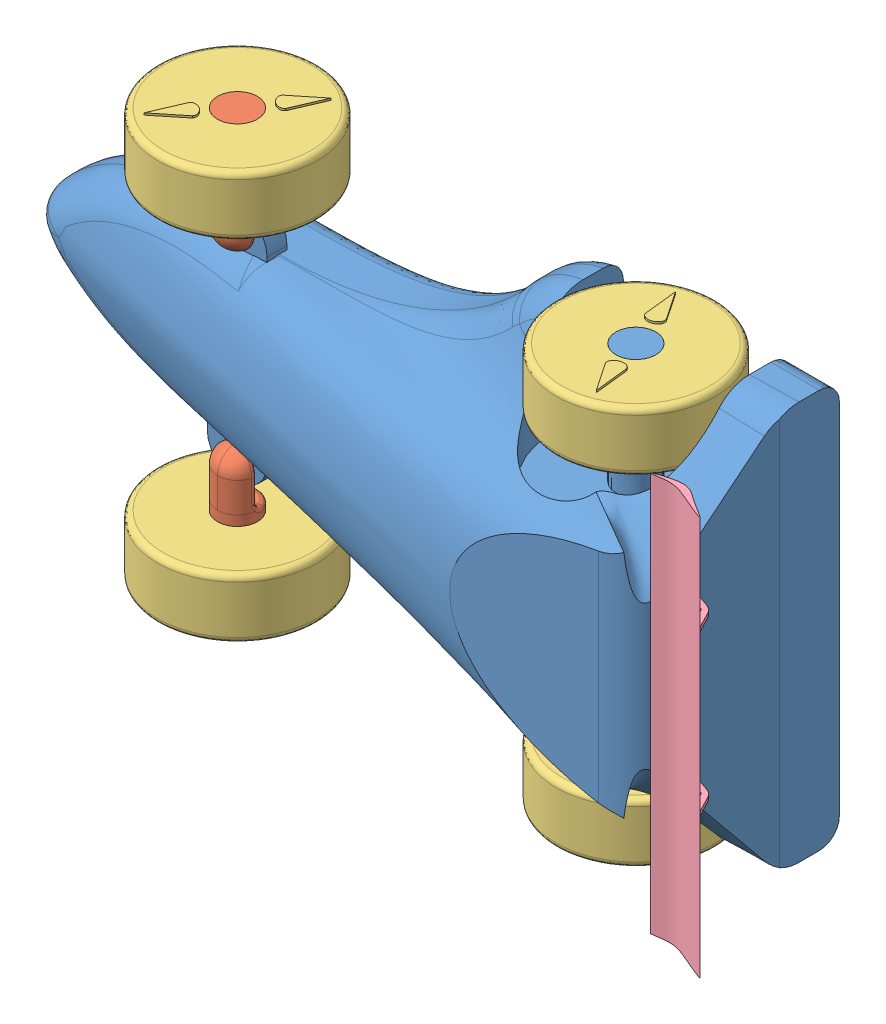
SolidWorks assembly Assembly_new, configuration Default. Lengths in mm.
Overall size (1020.36 525.36 306.14).
8 component instances, 4 part files, 15 mates.
Components (placement in the parent):
- carbody_new-1: carbody_new [Default] at origin size (961.64 514.49 238.28)
- Stub_new-1: Stub_new [Default] at (-701.6451 -107.7412 -10.9608) x (0 -1 0) z (-1 0 0) size (152.4 63.5 50.8)
- Wheel_new-1: Wheel_new [Default] at (-676.2451 -183.9412 14.4392) x (-0.599129 0 -0.800652) z (0 -1 0) size (203.2 203.2 78.74)
- Stub_new-2: Stub_new [Default] at (-650.8451 107.7412 -10.9608) x (0 1 0) z (1 0 0) size (152.4 63.5 50.8)
- Wheel_new-2: Wheel_new [Default] at (-168.5786 -177.8 14.4392) x (-0.909191 0 -0.41638) z (0 -1 0) size (203.2 203.2 78.74)
- Wheel_new-3: Wheel_new [Default] at (-168.5786 177.8 14.4392) x (-0.344076 0 -0.938942) z (0 1 0) size (203.2 203.2 78.74)
- Wheel_new-4: Wheel_new [Default] at (-676.2451 183.9412 14.4392) x (-0.605033 0 0.796201) z (0 1 0) size (203.2 203.2 78.74)
- Spoiler_new-1: Spoiler_new [Default] at (12.7984 -1.696 137.6523) x (-0.98555 0 0.169386) z (0 1 0) size (82.87 83.3 508)
Mates (geometry in assembly coordinates):
- Concentric1: concentric aligned: cylinder of carbody_new-1 through (-676.2451 -126.7912 -113.3899) axis (0 0 1) radius 19.05; cylinder of Stub_new-1 through (-676.2451 -126.7912 -23.6608) axis (0 0 1) radius 19.05
- Coincident2: coincident anti-aligned: plane of carbody_new-1 through (-714.6786 -152.4 14.4392) normal (0 0 1); plane of Stub_new-1 through (-600.0451 -107.7412 14.4392) normal (0 0 -1)
- Concentric2: concentric aligned: cylinder of Stub_new-1 through (-676.2451 -260.1412 14.4392) axis (0 1 0) radius 25.4; cylinder of Wheel_new-1 through (-676.2451 -260.1412 14.4392) axis (0 1 0) radius 25.4
- Coincident5: coincident aligned: plane of Stub_new-1 through (-701.6451 -260.1412 -10.9608) normal (0 -1 0); plane of Wheel_new-1 through (-676.2451 -260.1412 14.4392) normal (0 -1 0)
- Concentric3: concentric aligned: cylinder of carbody_new-1 through (-676.2451 126.7912 -85.8728) axis (0 0 1) radius 19.05; cylinder of Stub_new-2 through (-676.2451 126.7912 -23.6608) axis (0 0 1) radius 19.05
- Coincident6: coincident anti-aligned: plane of carbody_new-1 through (-714.6786 -152.4 14.4392) normal (0 0 1); plane of Stub_new-2 through (-752.4451 107.7412 14.4392) normal (0 0 -1)
- Concentric4: concentric aligned: cylinder of Stub_new-2 through (-676.2451 260.1412 14.4392) axis (0 -1 0) radius 25.4; cylinder of Wheel_new-4 through (-676.2451 260.1412 14.4392) axis (0 -1 0) radius 25.4
- Coincident7: coincident aligned: plane of Stub_new-2 through (-650.8451 260.1412 -10.9608) normal (0 1 0); plane of Wheel_new-4 through (-676.2451 260.1412 14.4392) normal (0 1 0)
- Concentric5: concentric aligned: cylinder of carbody_new-1 through (-168.5786 325.842 14.4392) axis (0 -1 0) radius 25.4; cylinder of Wheel_new-3 through (-168.5786 254 14.4392) axis (0 -1 0) radius 25.4
- Coincident8: coincident aligned: plane of carbody_new-1 through (-248.6828 254 -76.2) normal (0 1 0); plane of Wheel_new-3 through (-168.5786 254 14.4392) normal (0 1 0)
- Concentric6: concentric anti-aligned: cylinder of carbody_new-1 through (-168.5786 325.842 14.4392) axis (0 -1 0) radius 25.4; cylinder of Wheel_new-2 through (-168.5786 -254 14.4392) axis (0 1 0) radius 25.4
- Coincident9: coincident aligned: plane of carbody_new-1 through (-248.6828 -254 -76.2) normal (0 -1 0); plane of Wheel_new-2 through (-168.5786 -254 14.4392) normal (0 -1 0)
- Coincident10: coincident anti-aligned: plane of carbody_new-1 through (-38.9633 59.7593 152.4) normal (0.968837 0 0.247697); plane of Spoiler_new-1 through (-24.188 104.984 94.6084) normal (-0.968837 0 -0.247697)
- Coincident11: coincident anti-aligned: plane of carbody_new-1 through (-38.9633 59.7593 152.4) normal (0.968837 0 0.247697); plane of Spoiler_new-1 through (-24.188 -98.216 94.6084) normal (-0.968837 0 -0.247697)
- Parallel1: parallel anti-aligned: line of carbody_new-1 through (-29.1925 108.4686 114.183) axis (0 -1 0); face of Spoiler_new-1
